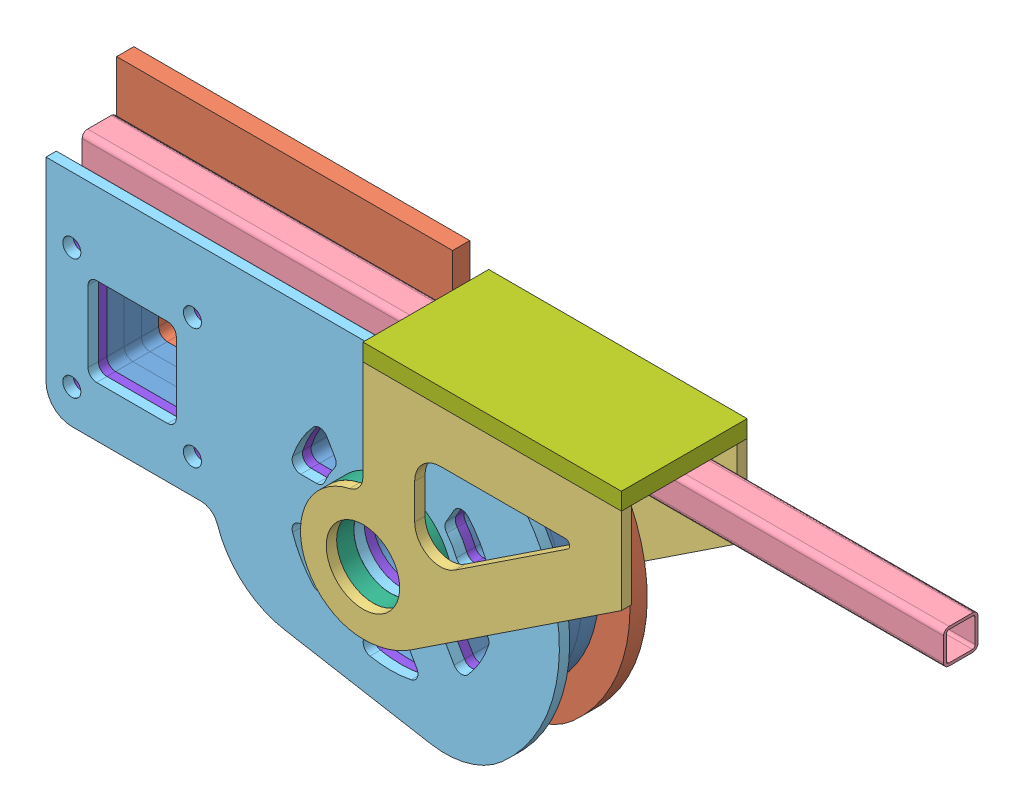
SolidWorks assembly bender, configuration Default. Lengths in mm.
Overall size (500 214.05 73).
12 component instances, 9 part files, 32 mates.
Components (placement in the parent):
- base1-1: base1 [Default] at origin size (280 160 10)
- base1-2: base1 [Default] at (0 0 -10) size (280 160 10)
- base2-1: base2 [Default] at (0 0 -20) size (298 214.05 10)
- handle-1: handle [Default] at (0 0 -26) size (186.3 139.3 6)
- handle-2: handle [Default] at (0 0 41) size (186.3 139.3 6)
- SHS20x20-1: SHS20x20 [[044] 20 x 20 x 1.6  SHS Tubeline Grade C350L0 (AS 1163)] at (50 90 0) x (0 1 0) z (1 0 0) size (20 20 500)
- base3-1: base3 [Default] at (0 0 25) size (298 184.05 6)
- bush-1: bush [Default] at (0 0 31) x (0.877857 0.478923 0) z (0 0 1) size (72.6 72.6 10)
- backing plate-1: backing plate [Default] at (75 113 10.5) x (1 0 0) z (0 -1 0) size (150 73 10)
- base1-3: base1 [Default] at (0 0 10) size (280 160 10)
- base4-1: base4 [Default] at (0 0 20) size (280 160 5)
- mount1-1: mount1 [Default] at (-150 25 -26) size (100 100 6)
Mates (geometry in assembly coordinates):
- Concentric1: concentric aligned: cylinder of base1-1 through (0 0 10) axis (0 0 -1) radius 21.3; cylinder of base1-2 through (0 0 0) axis (0 0 -1) radius 21.3
- Coincident1: coincident anti-aligned: plane of base1-1 through (0 0 0) normal (0 0 -1); plane of base1-2 through (0 0 0) normal (0 0 1)
- Parallel1: parallel aligned: plane of base1-1 through (0 80 10) normal (0 1 0); plane of base1-2 through (0 80 0) normal (0 1 0)
- Coincident3: coincident anti-aligned: plane of base1-2 through (0 0 -10) normal (0 0 -1); plane of base2-1 through (0 0 -10) normal (0 0 1)
- Concentric2: concentric aligned: cylinder of base1-2 through (0 0 0) axis (0 0 -1) radius 21.3; cylinder of base2-1 through (0 0 -10) axis (0 0 -1) radius 21.3
- Coincident4: coincident aligned: plane of base1-2 through (-200 80 0) normal (-1 0 0); plane of base2-1 through (-200 80 -10) normal (-1 0 0)
- Concentric3: concentric aligned: cylinder of base2-1 through (0 0 -10) axis (0 0 -1) radius 21.3; cylinder of handle-1 through (0 0 -20) axis (0 0 -1) radius 21.3
- Coincident5: coincident anti-aligned: plane of base2-1 through (0 0 -20) normal (0 0 -1); plane of handle-1 through (0 13.7 -20) normal (0 0 1)
- Distance1: distance = 10 mm anti-aligned: plane of handle-2 through (0 13.7 41) normal (0 0 -1); plane of base3-1 through (0 0 31) normal (0 0 1)
- Concentric4: concentric aligned: cylinder of base1-1 through (0 0 10) axis (0 0 -1) radius 21.3; cylinder of handle-2 through (0 0 47) axis (0 0 -1) radius 21.3
- Coincident7: coincident anti-aligned: plane of base1-2 through (0 80 0) normal (0 1 0); plane of SHS20x20-1 through (300 80 6.8) normal (0 -1 0)
- Coincident8: coincident anti-aligned: plane of base2-1 through (0 0 -10) normal (0 0 1); plane of SHS20x20-1 through (300 96.8 -10) normal (0 0 -1)
- Coincident9: coincident aligned: plane of base1-1 through (-200 80 10) normal (-1 0 0); plane of SHS20x20-1 through (-200 96.8 6.8) normal (-1 0 0)
- Coincident10: coincident aligned: plane of handle-1 through (0 36.3 -20) normal (-1 0 0); plane of handle-2 through (0 36.3 47) normal (-1 0 0)
- Parallel2: parallel aligned: plane of base1-1 through (-200 80 10) normal (-1 0 0); plane of handle-2 through (0 36.3 47) normal (-1 0 0)
- Concentric5: concentric aligned: cylinder of base1-1 through (0 0 10) axis (0 0 -1) radius 21.3; cylinder of base3-1 through (0 0 31) axis (0 0 -1) radius 21.3
- Coincident12: coincident aligned: plane of base1-1 through (-200 80 10) normal (-1 0 0); plane of base3-1 through (-200 80 31) normal (-1 0 0)
- Concentric6: concentric aligned: cylinder of base3-1 through (0 0 31) axis (0 0 -1) radius 21.3; cylinder of bush-1 through (0 0 41) axis (0 0 -1) radius 21.3
- Coincident13: coincident anti-aligned: plane of base3-1 through (0 0 31) normal (0 0 1); plane of bush-1 through (0 0 31) normal (0 0 -1)
- Coincident14: coincident anti-aligned: plane of handle-1 through (0 103 -20) normal (0 1 0); plane of backing plate-1 through (150 103 47) normal (0 -1 0)
- Coincident15: coincident aligned: plane of handle-2 through (0 13.7 47) normal (0 0 1); plane of backing plate-1 through (0 103 47) normal (0 0 1)
- Coincident16: coincident aligned: plane of handle-2 through (0 36.3 47) normal (-1 0 0); plane of backing plate-1 through (0 103 -26) normal (-1 0 0)
- Concentric7: concentric aligned: cylinder of base1-1 through (0 0 10) axis (0 0 -1) radius 21.3; cylinder of base1-3 through (0 0 20) axis (0 0 -1) radius 21.3
- Coincident17: coincident aligned: circle of base1-1; circle of base1-3
- Coincident18: coincident aligned: plane of base1-1 through (-200 80 10) normal (-1 0 0); plane of base1-3 through (-200 80 20) normal (-1 0 0)
- Coincident20: coincident anti-aligned: plane of base1-3 through (0 0 20) normal (0 0 1); plane of base4-1 through (0 0 20) normal (0 0 -1)
- Concentric8: concentric aligned: cylinder of base1-3 through (0 0 20) axis (0 0 -1) radius 21.3; cylinder of base4-1 through (0 0 25) axis (0 0 -1) radius 21.3
- Coincident21: coincident aligned: plane of base1-3 through (-200 80 20) normal (-1 0 0); plane of base4-1 through (-200 80 25) normal (-1 0 0)
- Coincident22: coincident anti-aligned: plane of base3-1 through (0 0 25) normal (0 0 -1); plane of base4-1 through (0 0 25) normal (0 0 1)
- Coincident23: coincident anti-aligned: plane of base2-1 through (0 0 -20) normal (0 0 -1); plane of mount1-1 through (-100 75 -20) normal (0 0 1)
- Coincident24: coincident aligned: plane of base2-1 through (-129.375 50.625 -20.001) normal (0 -1 0); plane of mount1-1 through (-175.625 50.625 -26) normal (0 -1 0)
- Coincident25: coincident aligned: plane of base2-1 through (-124.375 4.375 -20.001) normal (-1 0 0); plane of mount1-1 through (-124.375 -0.625 -26) normal (-1 0 0)
